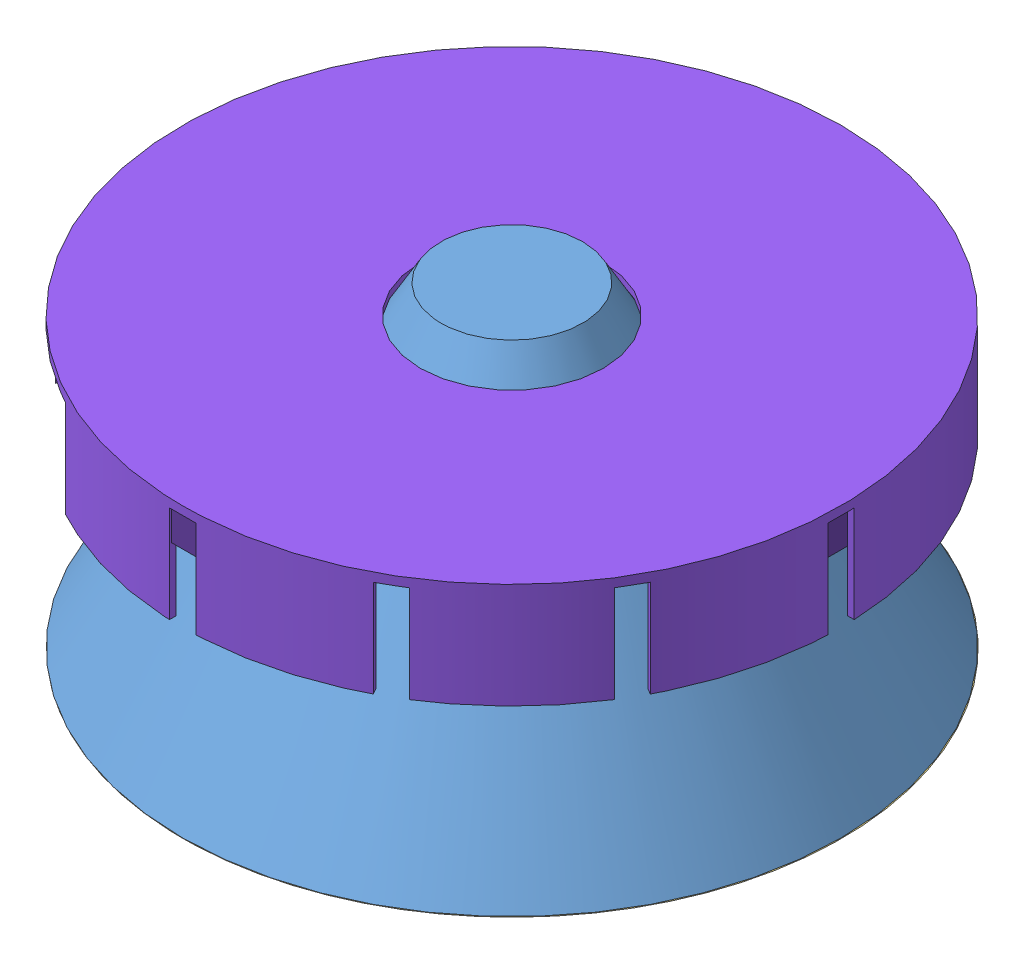
SolidWorks assembly Aeroshell, configuration Default. Lengths in mm.
Overall size (5000 2906.08 5006.18).
24 component instances, 19 part files, 4 mates.
Components (placement in the parent):
- Aeroshell-1: Aeroshell [Default] at origin size (5000 2400 5000)
- Shell_platform-1: Shell_platform [Default] at (0 -6.0807 -290.3722) size (4880 5 4880)
- Heatshield-2: Heatshield [Default] at (0 -6.0807 -289.9832) size (5000 500 5000)
- TLS-1: TLS [Default] at (546.1998 194.1104 853.5417) size (100 100 207.41)
- MARCI-1: MARCI [Default] at (875.0511 241.327 764.8193) x (0 1 0) z (-1 0 0) size (91.44 139.7 71.12)
- MASPEX-1: MASPEX [Default] at (-25.9646 214.3299 -1050.0975) size (1000 500 350)
- SEIS-1: SEIS [Default] at (375.3991 208.1212 455.8003) size (300 300 300)
- solarDisk-1: solarDisk [Default] at (0 1382.782 -286.3686) size (5000 800 5000)
- payloadStructure-1: payloadStructure [Default] at (0 101.113 -286.3686) x (0.999976 0 -0.006933) z (0.006933 0 0.999976) size (3000 1300 3000)
- Power-1: Power [Default] at (0 238.099 -286.3686) x (0.999963 0 0.008641) z (-0.008641 0 0.999963) size (560 1100 560)
- payloadStructureCap-1: payloadStructureCap [Default] at (0 98.9896 -282.8274) size (2800 100 2800)
- dinitrogenTeTank-1: dinitrogenTeTank [Default] at (-2224.8888 1981.9547 -664.1718) size (329.4 329.4 329.4)
- propellantTank-3: propellantTank [Default] at (2219.8151 1978.1665 -603.0175) size (367.6 367.6 367.6)
- Telecommunications-1: Telecommunications [Default] at (-640.1939 166.9903 -153.3388) x (0 0 -1) z (1 0 0) size (1137.5 500 500)
- CDH-1: CDH [Default] at (887.8472 185.5639 129.3374) size (650 500 500)
- balloonFolded-1: balloonFolded [Default] at (-127.5968 1370.3812 -303.7981) size (1200 500 1200)
- Thrusters-1: Thrusters [Default] at (-2206.5916 1841.4913 -294.457) size (500 250 250)
- Thrusters-2: Thrusters [Default] at (2198.3507 1841.7122 -280.5469) size (500 250 250)
- Thrusters-3: Thrusters [Default] at (-1.0862 1879.8297 1944.9528) x (0 0 -1) z (1 0 0) size (500 250 250)
- Thrusters-4: Thrusters [Default] at (-10.7941 1872.7542 -2542.5496) x (0 0 -1) z (1 0 0) size (500 250 250)
- dinitrogenTeTank-4: dinitrogenTeTank [Default] at (707.9891 357.7286 -1029.6487) size (329.4 329.4 329.4)
- propellantTank-4: propellantTank [Default] at (924.2922 381.1647 -649.1975) size (367.6 367.6 367.6)
- ACS-1: ACS [Default] at (-769.0924 293.9054 -997.9203) size (975 500 500)
- heliumTank-1: heliumTank [Default] at (-137.5273 564.2028 720.3758) size (735.2 735.2 735.2)
Mates (geometry in assembly coordinates):
- Coincident17: coincident anti-aligned: plane of Shell_platform-1 through (0 -6.0807 -290.3722) normal (0 -1 0); plane of Heatshield-2 through (0 -6.0807 -289.9832) normal (0 1 0)
- Concentric1: concentric aligned: circle of Aeroshell-1; circle of solarDisk-1
- Concentric2: concentric aligned: circle of Aeroshell-1; circle of payloadStructure-1
- Concentric3: concentric aligned: circle of Aeroshell-1; circle of Power-1
